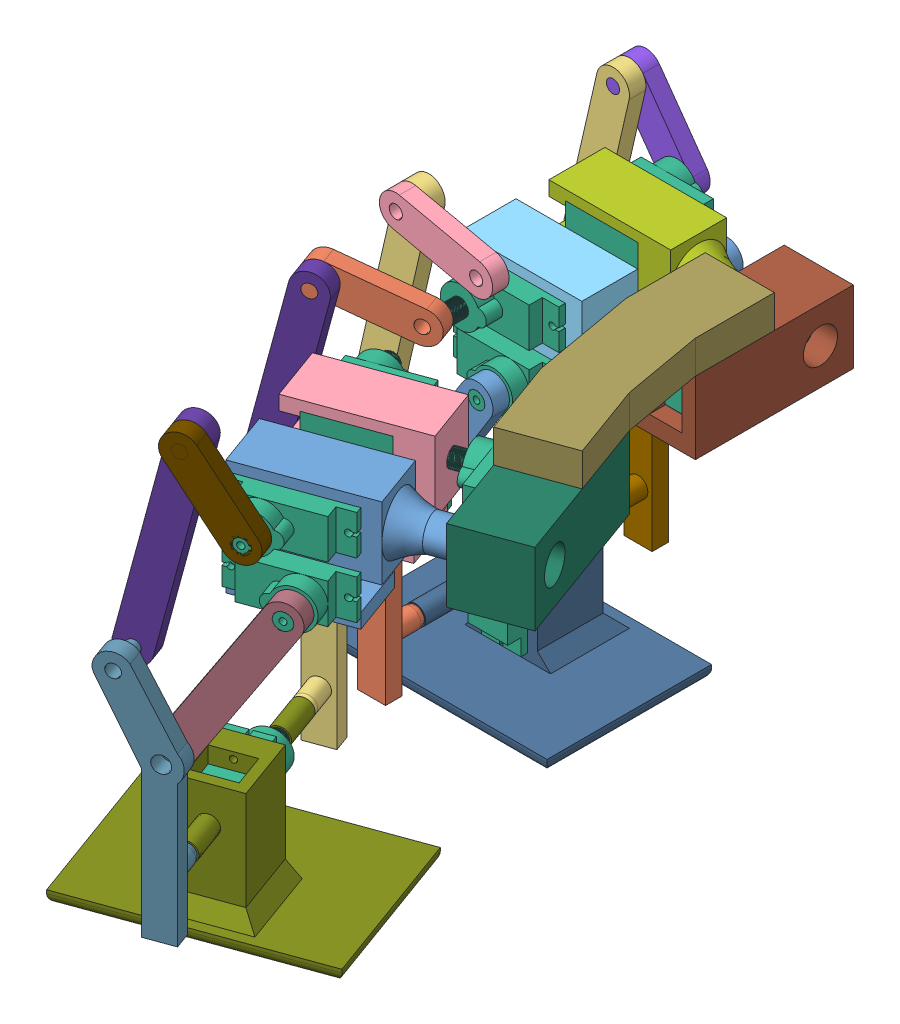
SolidWorks assembly prototype_both_legs_forshow, configuration Default. Lengths in mm.
Overall size (143.71 145.59 197.31).
37 component instances, 22 part files, 28 mates.
Components (placement in the parent):
- Femur_right_back-1: Femur_right_back [Default] at (-25.6615 10.28 -4) x (0.834573 -0.550898 0) z (0 0 1) size (11.2 59.99 5)
- Tibia_left-1: Tibia_left [Default] at (-26.436 7.6239 1) x (0.498529 0.866873 0) z (0 0 1) size (60.64 52.18 15)
- Femur_right_front_upper-1: Femur_right_front_upper [Default] at (-30.2379 -7.6747 -9) x (-0.171513 -0.985182 0) z (0 0 1) size (69.92 13.18 5)
- Femur_left_upper-9: Femur_left_upper [Default] at (-55.6198 -1.1687 -4) x (0.644038 -0.764993 0) z (0 0 1) size (29.81 25.25 10)
- Femur_servo_case_left-1: Femur_servo_case_left [Default] at origin size (37 35 17)
- servo motor (mg90s) v1.step-1: servo motor (mg90s) v1.step [Default] at (0.1122 49.9799 -32) size (32 12 33)
- servo motor (mg90s) v1.step-2: servo motor (mg90s) v1.step [Default] at (0.1122 66.9799 -32) x (-1 0 0) z (0 0 1) size (32 12 33)
- Femur_servo_case_right-1: Femur_servo_case_right [Default] at (0 0 -27) size (67 35 20.15)
- servo motor (mg90s) v1.step-4: servo motor (mg90s) v1.step [Default] at (0.1122 66.9799 -42) x (-1 0 0) z (0 0 -1) size (32 12 33)
- servo motor (mg90s) v1.step-5: servo motor (mg90s) v1.step [Default] at (0.1122 49.9799 -42) x (1 0 0) z (0 0 -1) size (32 12 33)
- Femur_right_upper-9: Femur_right_upper [Default] at (-6.5842 -7.4255 -75) x (0.940019 -0.341122 0) z (0 0 1) size (30.59 24.17 10)
- Femur_right_front_upper-2: Femur_right_front_upper [Default] at (-30.2379 -7.6747 -70) x (-0.171513 -0.985182 0) z (0 0 1) size (69.92 13.18 5)
- Femur_right_back-2: Femur_right_back [Default] at (0.8555 52.6222 -70) x (0.859981 -0.510325 0) z (0 0 -1) size (11.2 59.99 5)
- Tibia_right-1: Tibia_right [Default] at (-26.436 7.6239 -80) x (0.498529 0.866873 0) z (0 0 1) size (60.64 52.18 15)
- servo motor (mg90s) v1.step-6: servo motor (mg90s) v1.step [Default] at (-21.8096 -29.2141 -52.4) x (0 1 0) z (0 0 1) size (32 12 33)
- servo motor (mg90s) v1.step-12: servo motor (mg90s) v1.step [Default] at (54.1122 65.0424 -28.5) x (0 0 1) z (-1 0 0) size (32 12 33)
- foot-1: foot [Default] at (-36.2934 69.3284 -11.0239) size (70 38 59)
- Hip_motor_case_right-1: Hip_motor_case_right [Default] at origin size (21 22 48)
- Part6-1: Part6 [Default] at origin size (33.49 10 78.04)
- MirrorFemur_right_back-9: MirrorFemur_right_back [Default] at (28.2607 52.6222 85.4224) x (0.808118 -0.510325 -0.294131) z (-0.34202 0 -0.939693) size (11.2 59.99 5)
- MirrorTibia_right-5: MirrorTibia_right [Default] at (6.0353 7.6239 104.1536) x (0.468464 0.866873 -0.170507) z (0.34202 0 0.939693) size (60.64 52.18 15)
- servo motor (mg90s) v1.step-31: servo motor (mg90s) v1.step [Default] at (0.9428 -29.2141 76.6357) x (0 1 0) z (-0.34202 0 -0.939693) size (32 12 33)
- servo motor (mg90s) v1.step-32: servo motor (mg90s) v1.step [Default] at (64.1118 65.0424 28.2103) x (-0.34202 0 -0.939693) z (-0.939693 0 0.34202) size (32 12 33)
- MirrorHip_motor_case_right-5: MirrorHip_motor_case_right [Default] at (3.5153 0 19.9365) x (0.939693 0 -0.34202) z (0.34202 0 0.939693) size (21 22 48)
- Mirrorfoot-5: Mirrorfoot [Default] at (-26.8189 69.3284 42.7087) x (0.939693 0 -0.34202) z (0.34202 0 0.939693) size (70 38 59)
- MirrorFemur_right_front_upper-9: MirrorFemur_right_front_upper [Default] at (-0.9576 -7.6747 96.057) x (-0.16117 -0.985182 0.058661) z (0.34202 0 0.939693) size (69.92 13.18 5)
- MirrorFemur_right_upper-11: MirrorFemur_right_upper [Default] at (22.9797 -7.4255 92.6654) x (0.883329 -0.341122 -0.321505) z (0.34202 0 0.939693) size (30.59 24.17 10)
- MirrorFemur_servo_case_right-5: MirrorFemur_servo_case_right [Default] at (12.7499 0 45.3082) x (0.939693 0 -0.34202) z (0.34202 0 0.939693) size (67 35 20.15)
- servo motor (mg90s) v1.step-33: servo motor (mg90s) v1.step [Default] at (14.5655 66.9799 49.9683) x (-0.939693 0 0.34202) z (-0.34202 0 -0.939693) size (32 12 33)
- MirrorFemur_right_front_upper-10: MirrorFemur_right_front_upper [Default] at (-21.8209 -7.6747 38.7357) x (-0.16117 -0.985182 0.058661) z (0.34202 0 0.939693) size (69.92 13.18 5)
- MirrorFemur_right_back-10: MirrorFemur_right_back [Default] at (-19.2305 10.28 32.472) x (0.784242 -0.550898 -0.285441) z (0.34202 0 0.939693) size (11.2 59.99 5)
- servo motor (mg90s) v1.step-34: servo motor (mg90s) v1.step [Default] at (17.9857 66.9799 59.3652) x (-0.939693 0 0.34202) z (0.34202 0 0.939693) size (32 12 33)
- servo motor (mg90s) v1.step-35: servo motor (mg90s) v1.step [Default] at (17.9857 49.9799 59.3652) x (0.939693 0 -0.34202) z (0.34202 0 0.939693) size (32 12 33)
- servo motor (mg90s) v1.step-36: servo motor (mg90s) v1.step [Default] at (14.5655 49.9799 49.9683) x (0.939693 0 -0.34202) z (-0.34202 0 -0.939693) size (32 12 33)
- MirrorFemur_left_upper-12: MirrorFemur_left_upper [Default] at (-47.3821 -1.1687 42.7184) x (0.605198 -0.764993 -0.220274) z (0.34202 0 0.939693) size (29.81 25.25 10)
- MirrorTibia_left-5: MirrorTibia_left [Default] at (-21.6684 7.6239 28.0385) x (0.468464 0.866873 -0.170507) z (0.34202 0 0.939693) size (60.64 52.18 15)
- MirrorFemur_servo_case_left-5: MirrorFemur_servo_case_left [Default] at (3.5153 0 19.9365) x (0.939693 0 -0.34202) z (0.34202 0 0.939693) size (37 35 17)
Mates (geometry in assembly coordinates):
- Concentric1: concentric aligned: circle of Femur_right_back-1; circle of Tibia_left-1
- Concentric2: concentric aligned: circle of Tibia_left-1; circle of Femur_right_front_upper-1
- Concentric3: concentric aligned: circle of Femur_right_front_upper-1; circle of Femur_left_upper-1
- Concentric4: concentric anti-aligned: circle of Femur_left_upper-1; circle of servo motor (mg90s) v1.step-2
- Concentric5: concentric aligned: circle of servo motor (mg90s) v1.step-4; circle of Femur_left_upper-2
- Concentric6: concentric aligned: circle of Femur_left_upper-2; circle of Femur_right_front_upper-2
- Concentric7: concentric aligned: circle of Femur_right_front_upper-2; circle of Tibia_right-1
- Concentric9: concentric anti-aligned: circle of Femur_right_back-1; circle of servo motor (mg90s) v1.step-1
- Coincident1: coincident anti-aligned: plane of Femur_right_back-1 through (-25.6615 10.28 1) normal (0 0 1); plane of Tibia_left-1 through (-26.436 7.6239 1) normal (0 0 -1)
- Coincident3: coincident anti-aligned: plane of Femur_right_front_upper-1 through (-32.8247 28.8474 -4) normal (0 0 1); plane of Femur_left_upper-9 through (-55.6198 -1.1687 -4) normal (0 0 -1)
- Coincident4: coincident anti-aligned: plane of Femur_left_upper-9 through (-55.6198 -1.1687 -4) normal (0 0 -1); plane of servo motor (mg90s) v1.step-2 through (-3.8998 66.9799 -4) normal (0 0 1)
- Coincident5: coincident anti-aligned: plane of servo motor (mg90s) v1.step-6 through (-21.8096 -29.2141 -52.4) normal (0 0 -1); plane of foot-1 through (-36.2934 -18.2141 -52.4) normal (0 0 1)
- Concentric10: concentric aligned: circle of servo motor (mg90s) v1.step-6; circle of foot-1
- Concentric11: concentric anti-aligned: circle of Tibia_left-1; circle of foot-1
- Concentric12: concentric anti-aligned: circle of Tibia_right-1; circle of foot-1
- Concentric13: concentric aligned: circle of Femur_right_back-2; circle of Tibia_right-1
- Concentric14: concentric anti-aligned: unknown of servo motor (mg90s) v1.step-5; unknown of Femur_right_back-2
- Coincident6: coincident anti-aligned: plane of Femur_right_upper-9 through (-6.5842 -7.4255 -70) normal (0 0 1); plane of Femur_right_front_upper-2 through (-32.8247 28.8474 -70) normal (0 0 -1)
- Coincident7: coincident anti-aligned: plane of servo motor (mg90s) v1.step-4 through (-3.8998 66.9799 -70) normal (0 0 -1); plane of Femur_right_upper-9 through (-6.5842 -7.4255 -70) normal (0 0 1)
- Coincident8: coincident anti-aligned: plane of Femur_right_back-2 through (0.8555 52.6222 -75) normal (0 0 -1); plane of Tibia_right-1 through (-26.436 7.6239 -75) normal (0 0 1)
- Coincident9: coincident anti-aligned: plane of servo motor (mg90s) v1.step-5 through (4.1242 49.9799 -70) normal (0 0 -1); plane of Femur_right_back-2 through (0.8555 52.6222 -70) normal (0 0 1)
- Concentric15: concentric aligned: unknown of servo motor (mg90s) v1.step-6; unknown of foot-1
- Coincident10: coincident anti-aligned: plane of Femur_right_back-1 through (-25.6615 10.28 -4) normal (0 0 -1); plane of servo motor (mg90s) v1.step-1 through (4.1242 49.9799 -4) normal (0 0 1)
- Parallel2: parallel anti-aligned: plane of foot-1 through (-36.2934 -51.2141 -11.0239) normal (0 -1 0)
- Parallel3: parallel aligned: plane of Tibia_left-1 through (-17.5369 7.6239 6) normal (1 0 0); plane of Tibia_right-1 through (-17.5369 7.6239 -75) normal (1 0 0)
- Parallel4: parallel aligned: plane of Tibia_left-1 through (-17.5369 7.6239 6) normal (1 0 0)
- Distance1: distance = 8.6 mm anti-aligned: plane of foot-1 through (-21.8096 -24.2141 -66.4) normal (0 0 -1); plane of Tibia_right-1 through (-26.436 7.6239 -75) normal (0 0 1)
- Parallel5: parallel aligned: plane of Femur_right_front_upper-1 through (-37.6982 29.9653 -4) normal (-0.97469 0.223563 0); plane of Femur_right_front_upper-2 through (-37.6982 29.9653 -65) normal (-0.97469 0.223563 0)
